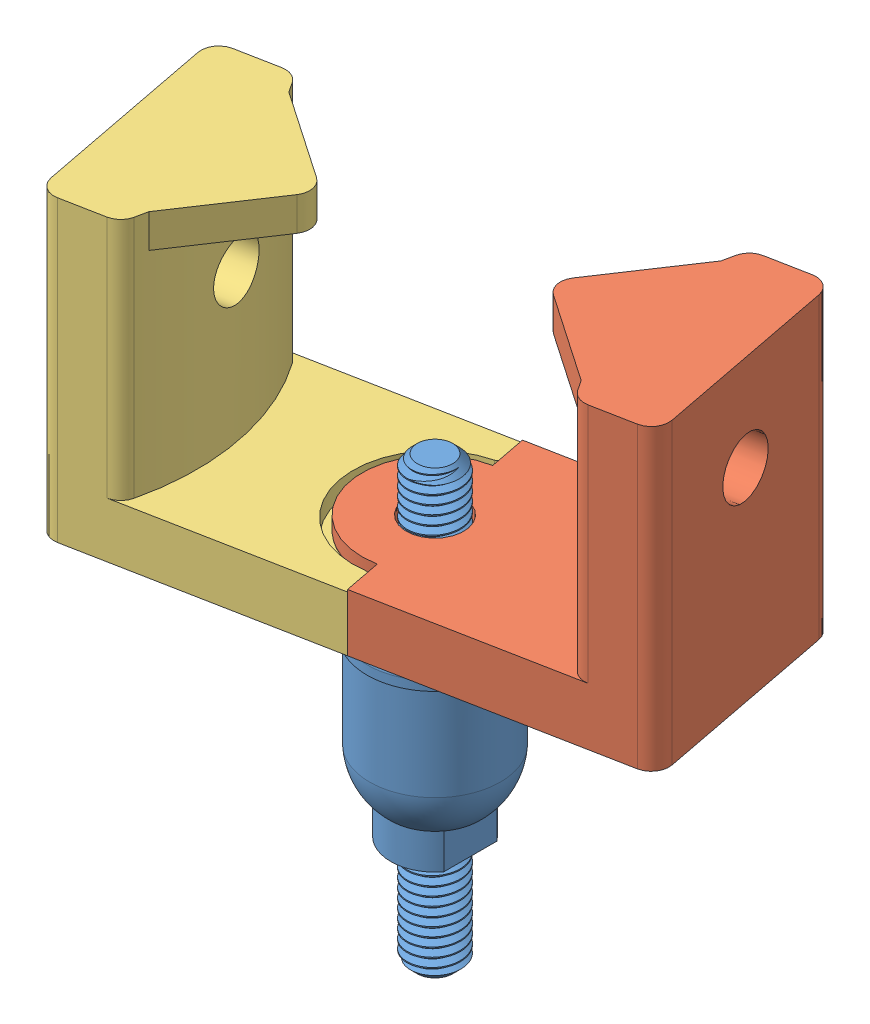
SolidWorks assembly TestStand, configuration Default. Lengths in mm.
Overall size (63.65 71.4 35.93).
3 component instances, 3 part files, 5 mates.
Components (placement in the parent):
- BallJoint-1: BallJoint [8412K11] x (-1 0 0) z (0 0 1) size (15.36 50.2 15.36)
- DroneMountBracket_d-1: DroneMountBracket_d [Default] at (0 11 0) x (0.981842 0 -0.189699) z (0.189699 0 0.981842) size (38.25 33.8 25)
- DroneMountBracket_s-1: DroneMountBracket_s [Default] at (0 11 0) x (-0.981842 0 0.189699) z (-0.189699 0 -0.981842) size (38.25 33.8 25)
Mates (geometry in assembly coordinates):
- Concentric1: concentric anti-aligned: circle of BallJoint-1; cylinder of DroneMountBracket_d-1 through (0 17.5 0) axis (0 -1 0) radius 3.25
- Concentric2: concentric anti-aligned: circle of BallJoint-1; cylinder of DroneMountBracket_s-1 through (0 15.25 0) axis (0 -1 0) radius 3.25
- Coincident1: coincident anti-aligned: plane of BallJoint-1 through (0 11 0) normal (0 1 0); plane of DroneMountBracket_d-1 through (0 11 0) normal (0 -1 0)
- Coincident2: coincident aligned: plane of DroneMountBracket_d-1 through (0 11 0) normal (0 -1 0); plane of DroneMountBracket_s-1 through (0 11 0) normal (0 -1 0)
- Parallel1: parallel aligned: plane of DroneMountBracket_d-1 through (2.3712 13 12.273) normal (0.189699 0 0.981842); plane of DroneMountBracket_s-1 through (2.3712 13.25 12.273) normal (0.189699 0 0.981842)
